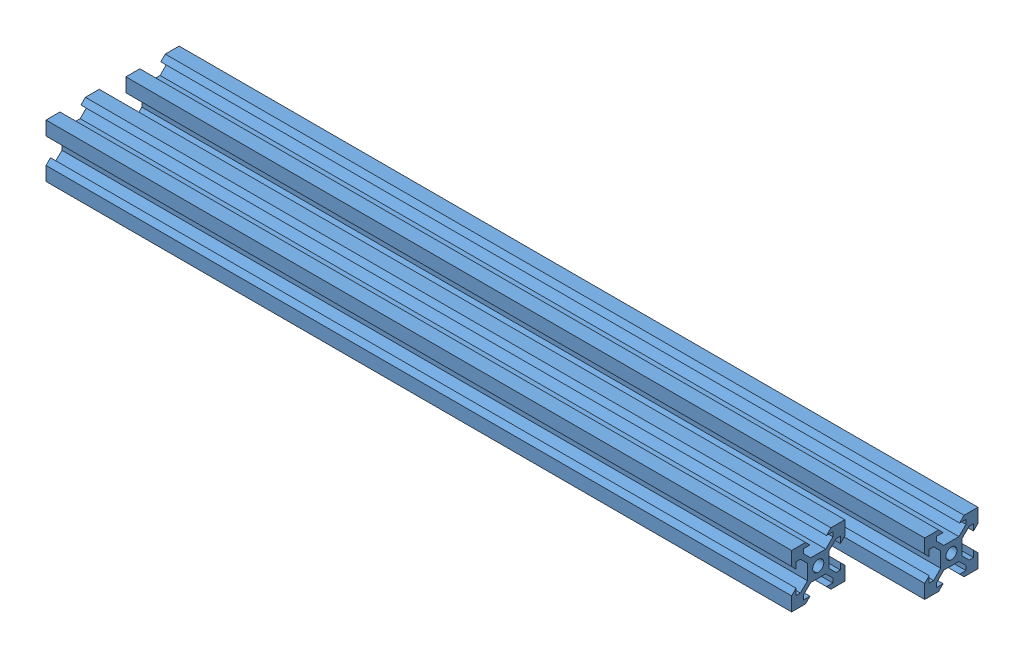
SolidWorks assembly Extrusion_for_drawing, configuration Default. Lengths in mm.
Overall size (300 20.95 50).
2 component instances, 1 part files, 3 mates.
Components (placement in the parent):
- V-slot-aluminum-1: V-slot-aluminum [side] at (-200.0963 -7.4717 201.3046) x (0 0 1) z (1 0 0) size (20 20 300)
- V-slot-aluminum-5: V-slot-aluminum [Gantry] at (-200.0963 -6.5227 231.3046) x (0 0 -1) z (1 0 0) size (20 20 280)
Mates (geometry in assembly coordinates):
- Parallel2: parallel anti-aligned: plane of V-slot-aluminum-1 through (99.9037 -2.6967 211.3046) normal (0 0 1); plane of V-slot-aluminum-5 through (79.9037 3.4773 221.3046) normal (0 0 -1)
- Coincident5: coincident aligned: plane of V-slot-aluminum-1 through (-200.0963 -7.4717 201.3046) normal (-1 0 0); plane of V-slot-aluminum-5 through (-200.0963 -6.5227 231.3046) normal (-1 0 0)
- Distance1: distance = 10 mm anti-aligned: plane of V-slot-aluminum-5 through (79.9037 3.4773 221.3046) normal (0 0 -1); plane of V-slot-aluminum-1 through (99.9037 -2.6967 211.3046) normal (0 0 1)
